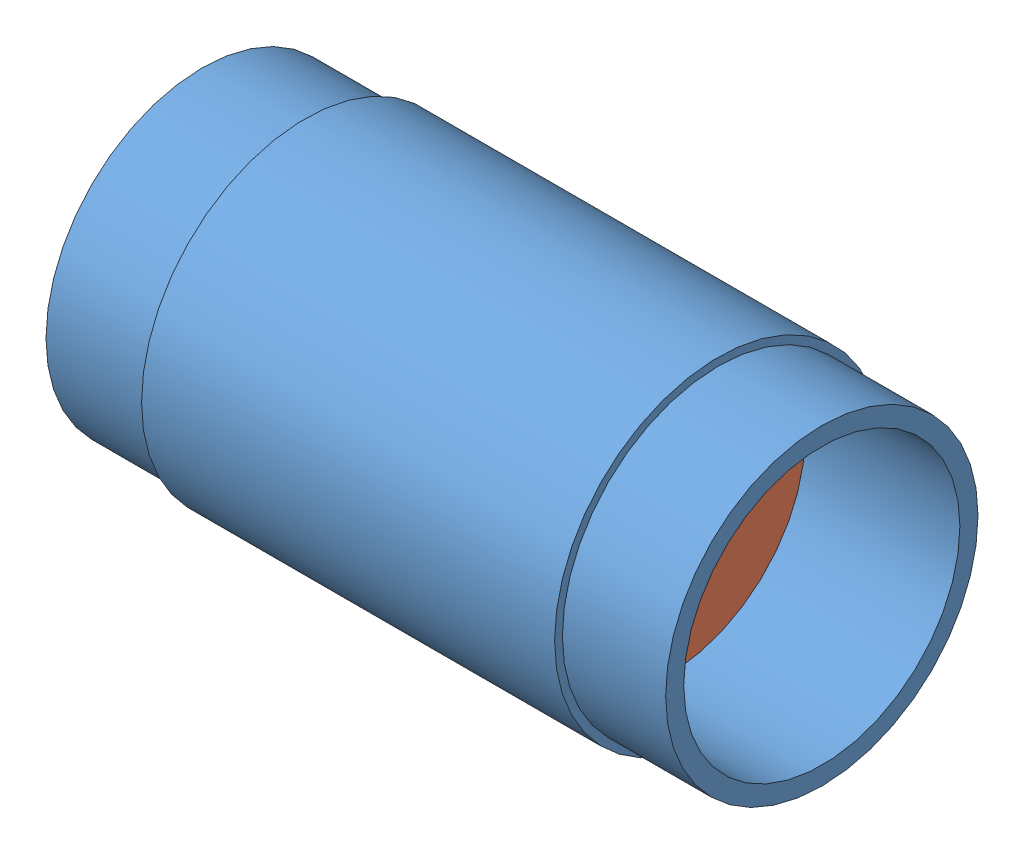
SolidWorks assembly Assem1, configuration Default. Lengths in mm.
Overall size (60 31.75 31.75).
3 component instances, 3 part files, 4 mates.
Components (placement in the parent):
- casing_v1-0-1: casing_v1-0 [Default] at (-27.4642 5.0974 -4.8012) size (60 31.75 31.75)
- filter_mock_v1-0-1: filter_mock_v1-0 [Default] at (17.4139 5.0974 -4.8012) x (0 0 -1) z (1 0 0) size (28.25 28.25 0.12)
- o-ring-1: o-ring [Default] at (15.8264 5.0974 -4.8012) x (0 0 -1) z (1 0 0) size (28.25 28.25 1.59)
Mates (geometry in assembly coordinates):
- Parallel2: parallel anti-aligned: plane of casing_v1-0-1 through (17.5358 5.0974 -4.8012) normal (-1 0 0); plane of filter_mock_v1-0-1 through (17.5358 5.0974 -4.8012) normal (1 0 0)
- Concentric1: concentric anti-aligned: circle of casing_v1-0-1; circle of filter_mock_v1-0-1
- Coincident6: coincident: plane of ?; plane of ?
- Coincident7: coincident aligned: circle of ?; circle of ?
